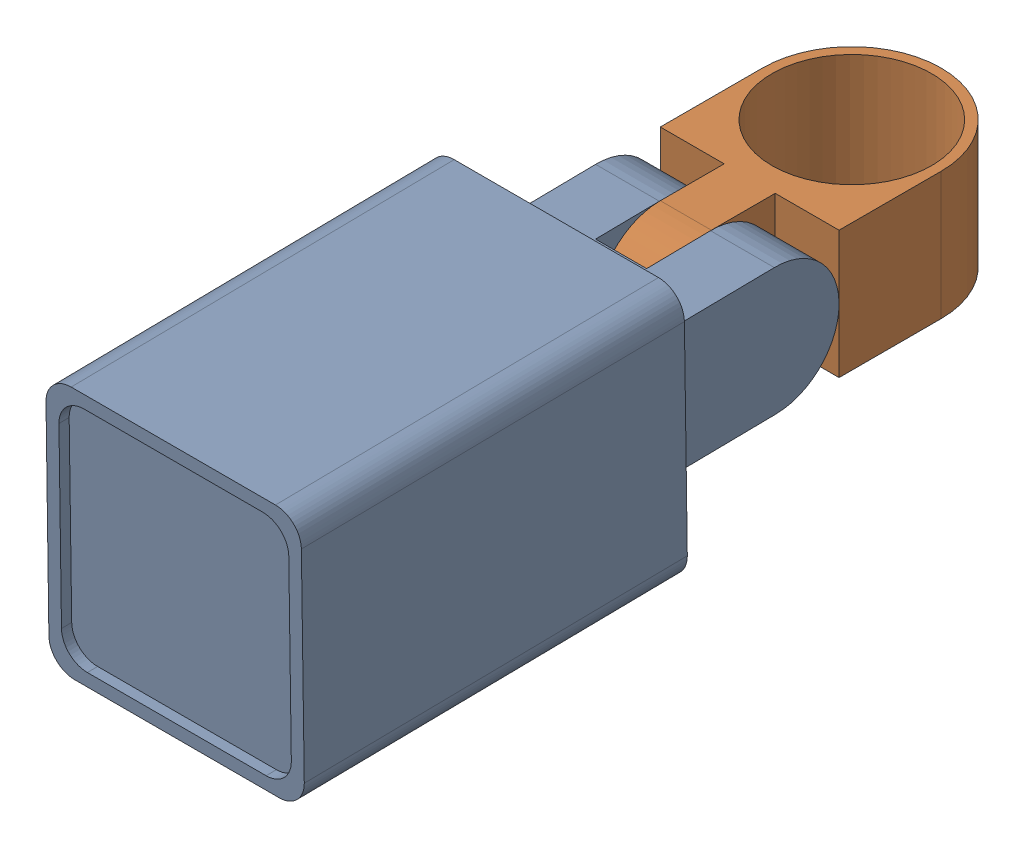
SolidWorks assembly Full CAmera, configuration Default. Lengths in mm.
Overall size (20 20.64 60.14).
2 component instances, 2 part files, 4 mates.
Components (placement in the parent):
- Camera 2-1: Camera 2 [Default] at (-12.8709 44.6916 13.6664) x (0 -0.01421 0.999899) z (0 0.999899 0.01421) size (45 20 20)
- Camera-2: Camera [Default] at (-5.8709 39.6916 0.6664) size (14 10 25)
Mates (geometry in assembly coordinates):
- Width1: width: plane of Camera 2-1 through (1.1291 44.6916 13.6664) normal (1 0 0); plane of Camera 2-1 through (-12.8709 44.6916 13.6664) normal (-1 0 0); plane of Camera-1 through (-22.7313 27.9051 21.3849) normal (-1 0 0); plane of Camera-1 through (-8.7313 27.9051 21.3849) normal (1 0 0)
- Concentric2: concentric anti-aligned: cylinder of Camera-1 through (-22.7313 22.9051 21.3849) axis (1 0 0) radius 5; cylinder of Camera 2-1 through (1.1291 44.6916 13.6664) axis (-1 0 0) radius 5
- Width2: width anti-aligned: plane of Camera-2 through (1.1291 49.6916 8.6664) normal (1 0 0); plane of Camera-2 through (-12.8709 49.6916 8.6664) normal (-1 0 0); plane of Camera 2-1 through (-12.8709 44.6916 13.6664) normal (-1 0 0); plane of Camera 2-1 through (1.1291 44.6916 13.6664) normal (1 0 0)
- Concentric3: concentric aligned: circle of Camera 2-1; circle of Camera-2
